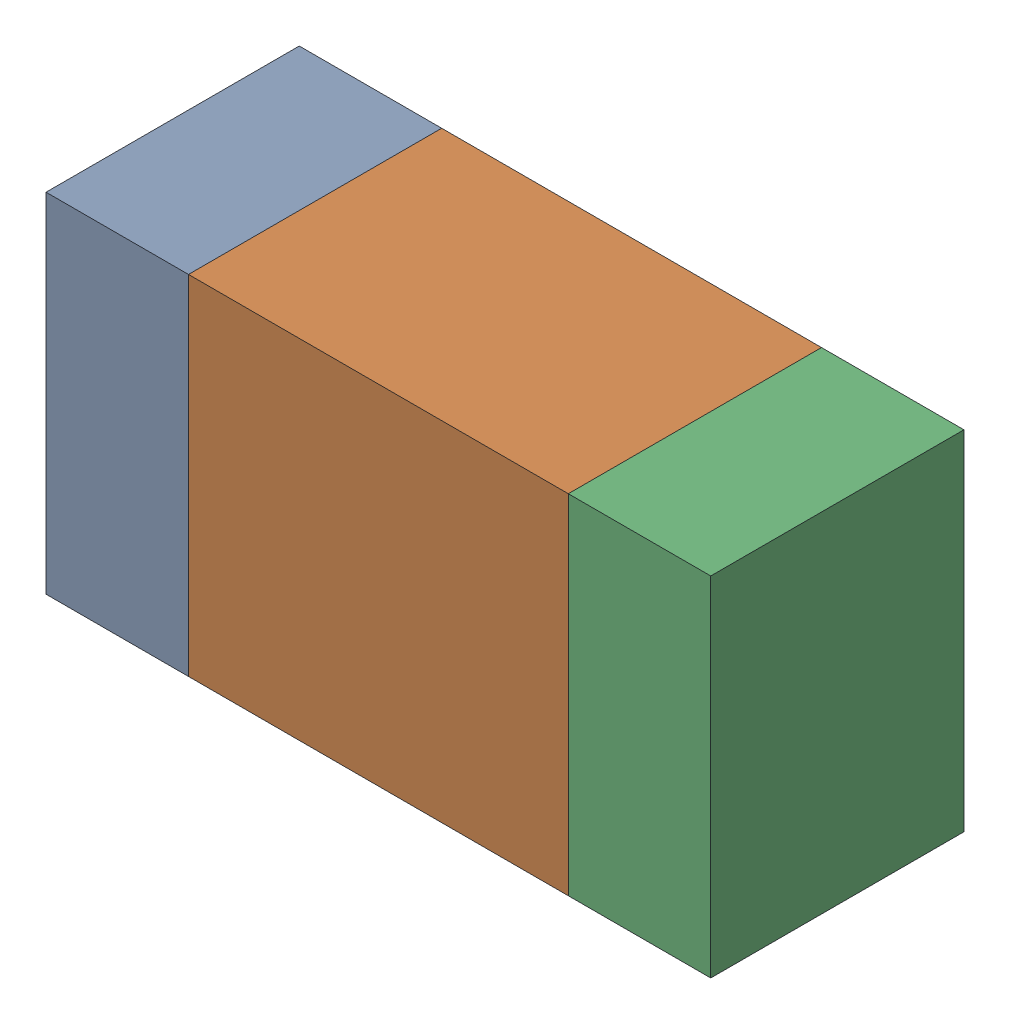
SolidWorks assembly R408PCB, configuration Default. Lengths in mm.
Overall size (1.05 0.55 0.4).
6 component instances, 2 part files, 0 mates.
Components (placement in the parent):
- 854785432-1: 854785432 [Default] at (121.9876 102.1001 0) size (0.22 0.55 0.4)
  - Extruded-1: Extruded [Default] at origin size (0.22 0.55 0.4)
- 854785568-1: 854785568 [Default] at (122.4001 102.1001 0) size (0.6 0.55 0.4)
  - Extruded_2-1: Extruded_2 [Default] at origin size (0.6 0.55 0.4)
- 854785432-2: 854785432 [Default] at (122.8126 102.1001 0) size (0.22 0.55 0.4)
  - Extruded-1: Extruded [Default] at origin size (0.22 0.55 0.4)
